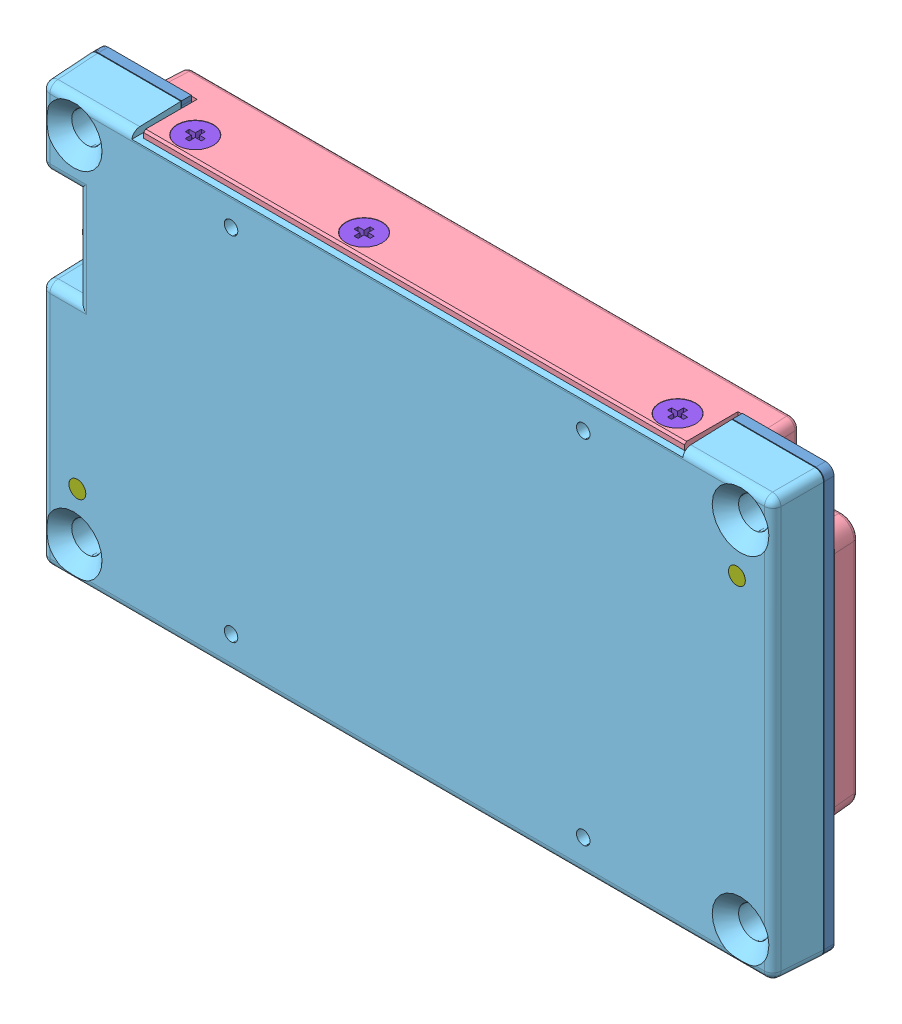
SolidWorks assembly TX2, configuration Default. Lengths in mm.
Overall size (87.07 50.04 12.4).
22 component instances, 10 part files, 0 mates.
Components (placement in the parent):
- 244-83310-1000-C03_ASM-1: 244-83310-1000-C03_ASM [Default] at origin size (87 50 7.77)
  - 142-83310-1000-C03-1: 142-83310-1000-C03 [Default] at origin size (87 50 1.16)
  - 080-0550-000_2-1: 080-0550-000_2 [Default] at (-2.36 33.789 1.164) size (3.63 4.07 1.47)
  - 080-0550-000_2-2: 080-0550-000_2 [Default] at (-2.36 28.232 1.164) size (3.63 4.07 1.47)
  - 080-1337-000_1-1: 080-1337-000_1 [Default] at (39.5 3.4 0) x (1 0 0) z (0 0 -1) size (70.16 10.74 5.05)
- P3310-BOTTOM-COVER--CNC-0316-1: P3310-BOTTOM-COVER--CNC-0316 [Default] at (83 8.88 -0.1484) x (-1 0 0) z (0 -1 0) size (87.03 9.23 36.85)
- TTP-186-DIE-REFERENCE-C00_ASM-1: TTP-186-DIE-REFERENCE-C00_ASM [Default] at (0.432 5.918 1.244) size (87.07 50.03 8.27)
  - 094-0021-004_1-1: 094-0021-004_1 [Default] at origin size (87.07 50.03 6.1)
  - 153-0369-000-PRELOAD-1: 153-0369-000-PRELOAD [Default] at (26.3174 29.151 5) x (1 0 0) z (0 1 0) size (8.1 3.29 7.91)
  - 153-0369-000-PRELOAD-2: 153-0369-000-PRELOAD [Default] at (51.8674 29.151 5) x (1 0 0) z (0 1 0) size (8.1 3.29 7.91)
  - 153-0369-000-PRELOAD-3: 153-0369-000-PRELOAD [Default] at (39.0874 5.9953 5) x (1 0 0) z (0 1 0) size (8.1 3.29 7.91)
  - PIN_8_00-DIE-REFERENCE-P3310-1: PIN_8_00-DIE-REFERENCE-P3310 [Default] at (0 0 -1.2) x (-1 0 0) z (0 1 0) size (2 8 2)
  - PIN_8_00-DIE-REFERENCE-P3310-2: PIN_8_00-DIE-REFERENCE-P3310 [Default] at (78.138 30.162 -1.2) x (-1 0 0) z (0 1 0) size (2 8 2)
  - 153-0368-000-1: 153-0368-000 [Default] at (39.0874 5.9953 1.73) x (-1 0 0) z (0 1 0) size (4.25 3.76 4.25)
  - 153-0368-000-2: 153-0368-000 [Default] at (26.3174 29.151 1.73) x (-1 0 0) z (0 1 0) size (4.25 3.76 4.25)
  - 153-0368-000-3: 153-0368-000 [Default] at (51.8674 29.151 1.73) x (-1 0 0) z (0 1 0) size (4.25 3.76 4.25)
  - PRESSURE-PLATE-P3310-C01-1: PRESSURE-PLATE-P3310-C01 [Default] at (39.0874 18.8953 2.9656) x (-1 0 0) z (0 -1 0) size (30.37 2.6 29.12)
- 155-0343-000-1: 155-0343-000 [Default] at (79 21 -1.1784) x (-1 0 0) z (0 0 -1) size (5.62 5.63 8.16)
- 155-0343-000-2: 155-0343-000 [Default] at (0 21 -1.1784) x (-1 0 0) z (0 0 -1) size (5.62 5.63 8.16)
- 153-0368-000-1: 153-0368-000 [Default] at (68.1416 45.009 3.6756) x (-1 0 0) z (0 0 1) size (4.25 3.76 4.25)
- 153-0368-000-2: 153-0368-000 [Default] at (31 45.009 3.6756) x (-1 0 0) z (0 0 1) size (4.25 3.76 4.25)
- 153-0368-000-3: 153-0368-000 [Default] at (11 45.009 3.6756) x (-1 0 0) z (0 0 1) size (4.25 3.76 4.25)
